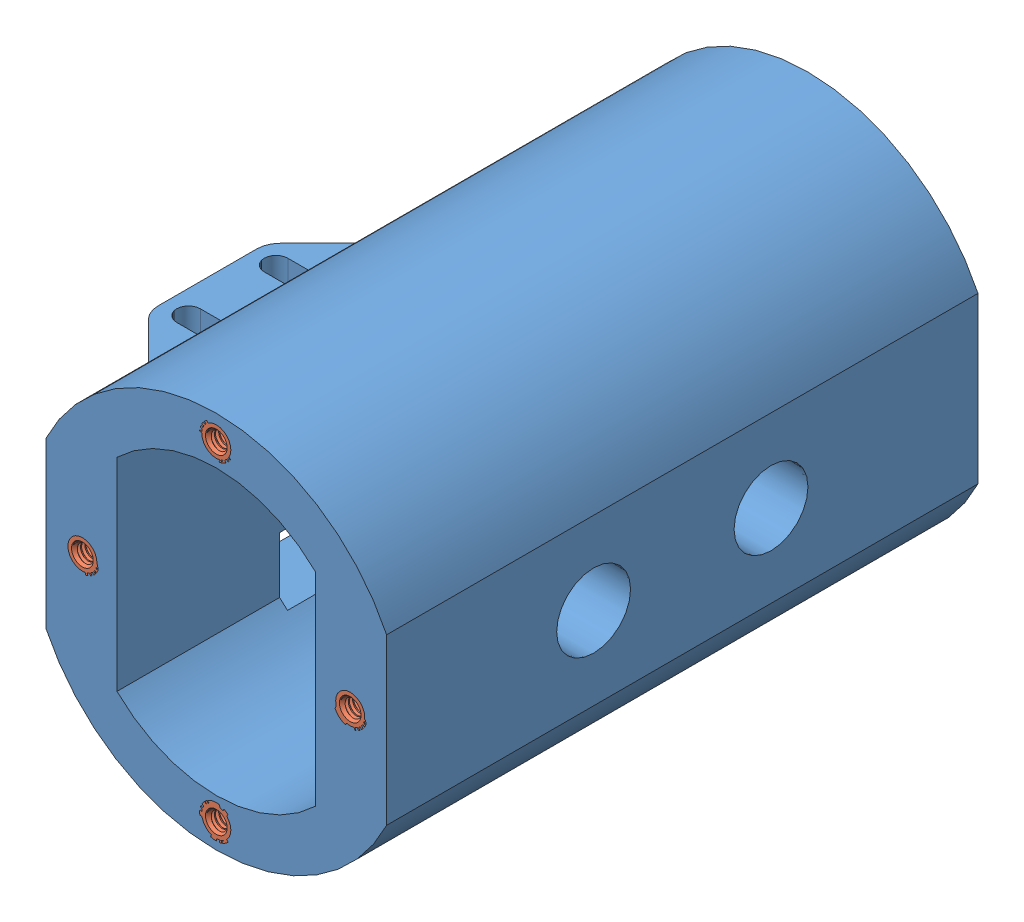
SolidWorks assembly Wing Fold Mechanism Main Shell, configuration Default. Lengths in mm.
Overall size (46.86 40.64 63.5).
9 component instances, 2 part files, 0 mates.
Components (placement in the parent):
- Wing Fold Mechanism Main Body-1: Wing Fold Mechanism Main Body [Default] at origin size (46.86 40.64 63.5)
- 93365A112-1: 93365A112 [Default] at (-14.378 0 55.5625) x (1 0 0) z (0 -1 0) size (3.58 4.78 3.58)
- 93365A112-2: 93365A112 [Default] at (0 17.68 55.5625) x (1 0 0) z (0 -1 0) size (3.58 4.78 3.58)
- 93365A112-3: 93365A112 [Default] at (14.378 0 55.5625) x (1 0 0) z (0 -1 0) size (3.58 4.78 3.58)
- 93365A112-4: 93365A112 [Default] at (0 -17.68 55.5625) x (1 0 0) z (0 -1 0) size (3.58 4.78 3.58)
- 93365A112-5: 93365A112 [Default] at (-14.378 0 -7.9375) x (1 0 0) z (0 1 0) size (3.58 4.78 3.58)
- 93365A112-6: 93365A112 [Default] at (14.378 0 -7.9375) x (1 0 0) z (0 1 0) size (3.58 4.78 3.58)
- 93365A112-7: 93365A112 [Default] at (0 -17.68 -7.9375) x (1 0 0) z (0 1 0) size (3.58 4.78 3.58)
- 93365A112-8: 93365A112 [Default] at (0 17.68 -7.9375) x (1 0 0) z (0 1 0) size (3.58 4.78 3.58)
